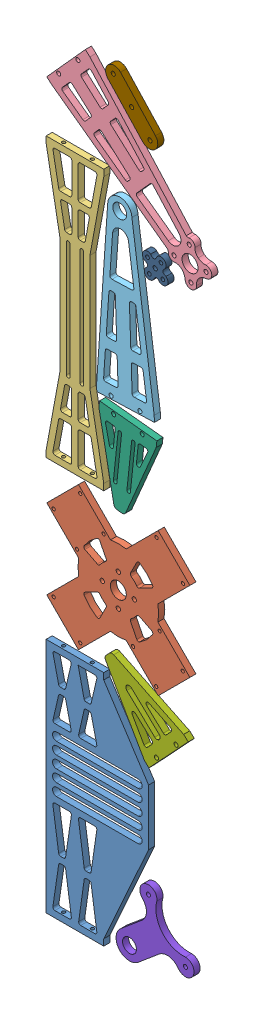
SolidWorks assembly Assem1, configuration Layout1[6061-T6 (SS)_4.763mm_Qnty1]. Lengths in mm.
Overall size (635.19 623.16 4.76).
10 component instances, 10 part files, 0 mates.
Components (placement in the parent):
- Camera Tray-1: Camera Tray [Default] at (27.5 71.5 0) x (0 1 0) z (-1 0 0) size (185 4.76 80)
- Handle Mount-1: Handle Mount [Default] at (61.3792 251.4208 -4.763) x (0.707107 -0.707107 0) z (-0.707107 -0.707107 0) size (123 4.76 123)
- Roll Bar-1: Roll Bar [Default] at (27.517 421.637 0) x (0 -1 0) z (0 0 -1) size (217.53 45.03 4.76)
- Pitch Arm Motor-1: Pitch Arm Motor [Default] at (117.3751 500.2009 -2.3815) x (0 0 -1) z (0.743145 -0.669131 0) size (4.76 45 143.6)
- Pitch Arm Bearing-1: Pitch Arm Bearing [Default] at (62.5079 508.3056 -2.3815) x (0 0 1) z (-0.034899 0.999391 0) size (4.76 45 139.76)
- Camera Tray Arm Motor-1: Camera Tray Arm Motor [Default] at (69.0873 369.7243 -2.3815) x (0 0 -1) z (-0.994522 0.104528 0) size (4.76 65 45)
- Camera Tray Arm Bearing-1: Camera Tray Arm Bearing [Default] at (100.5816 159.6093 -2.3815) x (0 0 1) z (-0.681998 -0.731354 0) size (4.76 65 45)
- Roll Arm Bearing Support-1: Roll Arm Bearing Support [Default] at (70.0992 15.5597 0) x (-0.642788 0.766044 0) z (0 0 -1) size (58.4 55.34 4.76)
- Yaw Slider Adj Bar-1: Yaw Slider Adj Bar [Default] at (71.7455 583.2732 0) x (0.681998 -0.731354 0) z (0.731354 0.681998 0) size (53.5 4.76 13.5)
- Roll Bar Motor Cross-1: Roll Bar Motor Cross [Default] at (90.1462 483.4538 0) x (0.139173 -0.990268 0) z (0 0 -1) size (18.61 18.61 4.76)
